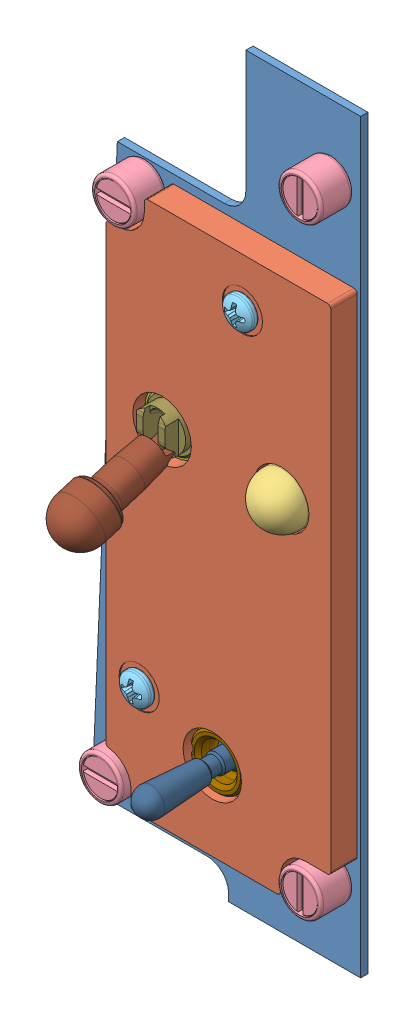
SolidWorks assembly APU ENG CRANK Panel Ref, configuration Default. Lengths in mm.
Overall size (59.41 165.1 40.02).
23 component instances, 12 part files, 0 mates.
Components (placement in the parent):
- APU ENG CRANK Mount Plate Ref-1: APU ENG CRANK Mount Plate Ref [Default] at origin size (59.41 165.1 1.59)
- APU ENG CRANK Light Plate Ref-1: APU ENG CRANK Light Plate Ref [Default] at origin size (49.78 118.75 5.84)
- APU Light Ref-1: APU Light Ref [Default] at origin size (11.43 11.43 11.43)
- D5 DZUS Stud Ref v1-1: D5 DZUS Stud Ref v1 [Default] at (-6.35 16.51 1.5875) size (9.65 9.65 8.83)
- D5 DZUS Stud Ref v1-2: D5 DZUS Stud Ref v1 [Default] at (-6.35 149.86 1.5875) size (9.65 9.65 8.83)
- D5 DZUS Stud Ref v1-3: D5 DZUS Stud Ref v1 [Default] at (-50.546 16.51 1.5875) x (0 1 0) z (0 0 1) size (9.65 9.65 8.83)
- D5 DZUS Stud Ref v1-4: D5 DZUS Stud Ref v1 [Default] at (-47.625 128.5875 1.5875) x (0 1 0) z (0 0 1) size (9.65 9.65 8.83)
- No. 6 Pan Head Phillips Machine Screw Ref v2-1: No. 6 Pan Head Phillips Machine Screw Ref v2 [Default] at (-43.18 37.084 4.0005) size (6.9 6.86 4.05)
- No. 6 Pan Head Phillips Machine Screw Ref v2-2: No. 6 Pan Head Phillips Machine Screw Ref v2 [Default] at (-20.32 120.65 4.0005) size (6.9 6.86 4.05)
- MS25081-4 v1-1: MS25081-4 v1 [Default] at (-26.9875 30.1625 -1.016) x (0 1 0) z (0 0 1) size (18.26 19.09 2.29)
- MS25081-4 v1-2: MS25081-4 v1 [Default] at (-38.1 88.9 -1.016) size (18.26 19.09 2.29)
- MS25082-8 v2-1: MS25082-8 v2 [Default] at (-26.9875 30.1625 -2.0066) size (15.08 16.48 1.98)
- MS25082-8 v2-2: MS25082-8 v2 [Default] at (-38.1 88.9 -2.0066) size (15.08 16.48 1.98)
- MS35333-126 v1-1: MS35333-126 v1 [Default] at (-26.9875 30.1625 1.8161) size (15.24 15.24 0.71)
- MS35333-126 v1-2: MS35333-126 v1 [Default] at (-38.1 88.9 1.8161) size (15.24 15.24 0.71)
- MS25082-8 v2-3: MS25082-8 v2 [Default] at (-26.9875 30.1625 3.0353) size (15.08 16.48 1.98)
- MS25082-8 v2-4: MS25082-8 v2 [Default] at (-38.1 88.9 3.0353) size (15.08 16.48 1.98)
- MS Toggle Switch Sealed 3-Position Ref v1-1: MS Toggle Switch Sealed 3-Position Ref v1 [Default] at origin size (14.29 14.29 30.73)
  - Toggle Threads Sealed Ref-1: Toggle Threads Sealed Ref [Default] at (-26.9875 30.1625 -5.2705) x (0 -1 0) z (0 0 1) size (14.29 14.29 13.21)
  - Toggle Lever Sealed Ref-1: Toggle Lever Sealed Ref [Default] at (-26.9875 30.1625 -5.2705) x (0 -1 0) z (0 0 1) size (10.67 7.94 27.59)
- MS Toggle Switch Locking F Ref v3-1: MS Toggle Switch Locking F Ref v3 [Default] at origin size (14.29 21.75 40.02)
  - Toggle Lever Locking Round Ref-1: Toggle Lever Locking Round Ref [Default] at (-38.1 90.6823 -6.2741) x (-1 0 0) z (0 -0.292372 0.956305) size (10.67 10.67 36.48)
  - Toggle Threads Locking Ref-1: Toggle Threads Locking Ref [Default] at (-38.1 88.9 -6.5405) x (-1 0 0) z (0 0 1) size (14.29 14.29 17.92)
